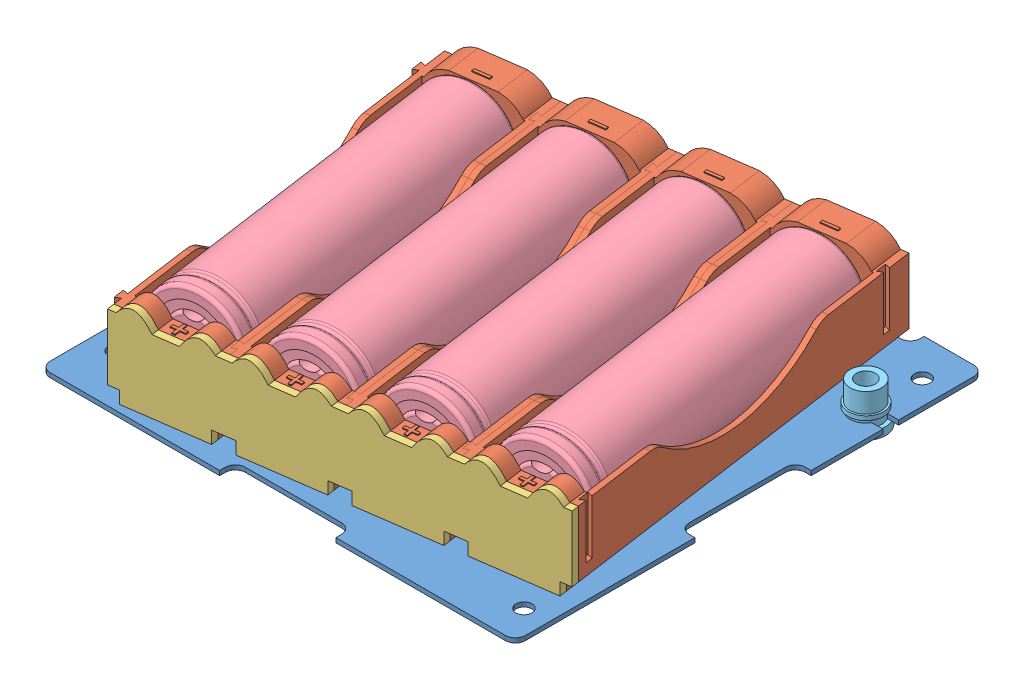
SolidWorks assembly M100 Battery Assembly, configuration Default. Lengths in mm.
Overall size (95.95 22.45 94.09).
45 component instances, 8 part files, 97 mates.
Components (placement in the parent):
- M103 Battery Plate-1: M103 Battery Plate [Default] at (-64.3857 -9.2767 40.2779) size (95.46 0.9 94.09)
- M102 Battery Holder Assembly-1: M102 Battery Holder Assembly [Default] at (-18.4887 8.3398 -10.8914) x (-0.990268 0 0.139173) z (-0.139173 0 -0.990268) size (83.6 18.9 79.5)
  - single battery holder-1: single battery holder [Default] at (-25.8788 -16.7165 25.0128) size (21.65 18.9 78)
  - single battery holder-2: single battery holder [Default] at (-5.2288 -16.7165 25.0128) size (21.65 18.9 78)
  - single battery holder-3: single battery holder [Default] at (15.4212 -16.7165 25.0128) size (21.65 18.9 78)
  - single battery holder-4: single battery holder [Default] at (36.0712 -16.7165 25.0128) size (21.65 18.9 78)
  - battery pack cap-1: battery pack cap [Default] at (36.0712 -16.7165 -52.9872) x (-1 0 0) z (0 0 -1) size (82.6 17.7 1.5)
- Battery, 18650_LGABC11865_3.7V-1: Battery, 18650_LGABC11865_3.7V [Default] at (9.3368 2.4733 1.1504) x (-0.990268 0 0.139173) z (0 1 0) size (18.3 64.95 18.3)
- Battery, 18650_LGABC11865_3.7V-2: Battery, 18650_LGABC11865_3.7V [Default] at (-11.1122 2.4733 4.0244) x (-0.990268 0 0.139173) z (0 1 0) size (18.3 64.95 18.3)
- Battery, 18650_LGABC11865_3.7V-3: Battery, 18650_LGABC11865_3.7V [Default] at (-31.5612 2.4733 6.8983) x (-0.990268 0 0.139173) z (0 1 0) size (18.3 64.95 18.3)
- Battery, 18650_LGABC11865_3.7V-4: Battery, 18650_LGABC11865_3.7V [Default] at (-52.0103 2.4733 9.7722) x (-0.990268 0 0.139173) z (0 1 0) size (18.3 64.95 18.3)
- grommet, 1-8in ID, 5269T211-2: grommet, 1-8in ID, 5269T211 [Default] at (21.2068 -2.8902 -24.7221) x (0.837169 0 0.546944) z (0.546944 0 -0.837169) size (7.94 7.94 7.94)
- screw, pan head, 0-80, 1_8L, 316SS, 91400A030-9: screw, pan head, 0-80, 1_8L, 316SS, 91400A030 [91400A030] at (-49.1372 -6.1017 -8.9448) x (-0.837169 0 -0.546944) z (0 -1 0) size (2.95 2.95 4.29)
- screw, pan head, 0-80, 1_8L, 316SS, 91400A030-10: screw, pan head, 0-80, 1_8L, 316SS, 91400A030 [91400A030] at (-39.4821 -6.1017 -10.3017) x (-0.837169 0 -0.546944) z (0 -1 0) size (2.95 2.95 4.29)
- screw, pan head, 0-80, 1_8L, 316SS, 91400A030-11: screw, pan head, 0-80, 1_8L, 316SS, 91400A030 [91400A030] at (-59.9311 -6.1017 -7.4278) x (-0.837169 0 -0.546944) z (0 -1 0) size (2.95 2.95 4.29)
- screw, pan head, 0-80, 1_8L, 316SS, 91400A030-12: screw, pan head, 0-80, 1_8L, 316SS, 91400A030 [91400A030] at (-28.6882 -6.1017 -11.8187) x (-0.837169 0 -0.546944) z (0 -1 0) size (2.95 2.95 4.29)
- screw, pan head, 0-80, 1_8L, 316SS, 91400A030-13: screw, pan head, 0-80, 1_8L, 316SS, 91400A030 [91400A030] at (-55.1157 -6.1017 26.8355) x (-0.837169 0 -0.546944) z (0 -1 0) size (2.95 2.95 4.29)
- screw, pan head, 0-80, 1_8L, 316SS, 91400A030-14: screw, pan head, 0-80, 1_8L, 316SS, 91400A030 [91400A030] at (-44.3218 -6.1017 25.3185) x (-0.837169 0 -0.546944) z (0 -1 0) size (2.95 2.95 4.29)
- screw, pan head, 0-80, 1_8L, 316SS, 91400A030-15: screw, pan head, 0-80, 1_8L, 316SS, 91400A030 [91400A030] at (17.0253 -6.1017 16.6967) x (1 0 0) z (0 -1 0) size (2.95 2.95 4.29)
- screw, pan head, 0-80, 1_8L, 316SS, 91400A030-16: screw, pan head, 0-80, 1_8L, 316SS, 91400A030 [91400A030] at (-34.6667 -6.1017 23.9615) x (-0.837169 0 -0.546944) z (0 -1 0) size (2.95 2.95 4.29)
- screw, pan head, 0-80, 1_8L, 316SS, 91400A030-17: screw, pan head, 0-80, 1_8L, 316SS, 91400A030 [91400A030] at (12.2099 -6.1017 -17.5666) x (-0.837169 0 -0.546944) z (0 -1 0) size (2.95 2.95 4.29)
- screw, pan head, 0-80, 1_8L, 316SS, 91400A030-18: screw, pan head, 0-80, 1_8L, 316SS, 91400A030 [91400A030] at (-19.0331 -6.1017 -13.1757) x (-0.837169 0 -0.546944) z (0 -1 0) size (2.95 2.95 4.29)
- screw, pan head, 0-80, 1_8L, 316SS, 91400A030-19: screw, pan head, 0-80, 1_8L, 316SS, 91400A030 [91400A030] at (-8.2391 -6.1017 -14.6926) x (-0.837169 0 -0.546944) z (0 -1 0) size (2.95 2.95 4.29)
- screw, pan head, 0-80, 1_8L, 316SS, 91400A030-20: screw, pan head, 0-80, 1_8L, 316SS, 91400A030 [91400A030] at (1.416 -6.1017 -16.0496) x (-0.837169 0 -0.546944) z (0 -1 0) size (2.95 2.95 4.29)
- screw, pan head, 0-80, 1_8L, 316SS, 91400A030-21: screw, pan head, 0-80, 1_8L, 316SS, 91400A030 [91400A030] at (-23.8728 -6.1017 22.4446) x (-0.837169 0 -0.546944) z (0 -1 0) size (2.95 2.95 4.29)
- screw, pan head, 0-80, 1_8L, 316SS, 91400A030-22: screw, pan head, 0-80, 1_8L, 316SS, 91400A030 [91400A030] at (-14.2177 -6.1017 21.0876) x (-0.837169 0 -0.546944) z (0 -1 0) size (2.95 2.95 4.29)
- screw, pan head, 0-80, 1_8L, 316SS, 91400A030-23: screw, pan head, 0-80, 1_8L, 316SS, 91400A030 [91400A030] at (-3.4238 -6.1017 19.5706) x (-0.837169 0 -0.546944) z (0 -1 0) size (2.95 2.95 4.29)
- screw, pan head, 0-80, 1_8L, 316SS, 91400A030-24: screw, pan head, 0-80, 1_8L, 316SS, 91400A030 [91400A030] at (6.2314 -6.1017 18.2137) x (-0.837169 0 -0.546944) z (0 -1 0) size (2.95 2.95 4.29)
- nut, 0-80, standard, 18-8SS, 91841A115-1: nut, 0-80, standard, 18-8SS, 91841A115 [91841A115] at (1.4049 -7.9267 -16.0638) x (0.788011 0 -0.615661) z (0.615661 0 0.788011) size (3.97 1.19 5.04)
- nut, 0-80, standard, 18-8SS, 91841A115-2: nut, 0-80, standard, 18-8SS, 91841A115 [91841A115] at (-14.2177 -7.9267 21.0876) x (-0.990268 0 0.139173) z (-0.139173 0 -0.990268) size (3.97 1.19 5.04)
- nut, 0-80, standard, 18-8SS, 91841A115-3: nut, 0-80, standard, 18-8SS, 91841A115 [91841A115] at (-3.4238 -7.9267 19.5706) x (-0.990268 0 0.139173) z (-0.139173 0 -0.990268) size (3.97 1.19 5.04)
- nut, 0-80, standard, 18-8SS, 91841A115-4: nut, 0-80, standard, 18-8SS, 91841A115 [91841A115] at (-8.2391 -7.9267 -14.6926) x (-0.990268 0 0.139173) z (-0.139173 0 -0.990268) size (3.97 1.19 5.04)
- nut, 0-80, standard, 18-8SS, 91841A115-5: nut, 0-80, standard, 18-8SS, 91841A115 [91841A115] at (-19.0331 -7.9267 -13.1757) x (-0.990268 0 0.139173) z (-0.139173 0 -0.990268) size (3.97 1.19 5.04)
- nut, 0-80, standard, 18-8SS, 91841A115-6: nut, 0-80, standard, 18-8SS, 91841A115 [91841A115] at (-39.4821 -7.9267 -10.3017) x (-0.990268 0 0.139173) z (-0.139173 0 -0.990268) size (3.97 1.19 5.04)
- nut, 0-80, standard, 18-8SS, 91841A115-7: nut, 0-80, standard, 18-8SS, 91841A115 [91841A115] at (-28.6882 -7.9267 -11.8187) x (-0.990268 0 0.139173) z (-0.139173 0 -0.990268) size (3.97 1.19 5.04)
- nut, 0-80, standard, 18-8SS, 91841A115-8: nut, 0-80, standard, 18-8SS, 91841A115 [91841A115] at (-23.8728 -7.9267 22.4446) x (-0.990268 0 0.139173) z (-0.139173 0 -0.990268) size (3.97 1.19 5.04)
- nut, 0-80, standard, 18-8SS, 91841A115-9: nut, 0-80, standard, 18-8SS, 91841A115 [91841A115] at (-34.6667 -7.9267 23.9615) x (-0.990268 0 0.139173) z (-0.139173 0 -0.990268) size (3.97 1.19 5.04)
- nut, 0-80, standard, 18-8SS, 91841A115-10: nut, 0-80, standard, 18-8SS, 91841A115 [91841A115] at (-59.9311 -7.9267 -7.4278) x (-0.990268 0 0.139173) z (-0.139173 0 -0.990268) size (3.97 1.19 5.04)
- nut, 0-80, standard, 18-8SS, 91841A115-11: nut, 0-80, standard, 18-8SS, 91841A115 [91841A115] at (-49.1372 -7.9267 -8.9448) x (-0.990268 0 0.139173) z (-0.139173 0 -0.990268) size (3.97 1.19 5.04)
- nut, 0-80, standard, 18-8SS, 91841A115-12: nut, 0-80, standard, 18-8SS, 91841A115 [91841A115] at (-44.3218 -7.9267 25.3185) x (-0.990268 0 0.139173) z (-0.139173 0 -0.990268) size (3.97 1.19 5.04)
- nut, 0-80, standard, 18-8SS, 91841A115-13: nut, 0-80, standard, 18-8SS, 91841A115 [91841A115] at (-55.1157 -7.9267 26.8355) x (-0.990268 0 0.139173) z (-0.139173 0 -0.990268) size (3.97 1.19 5.04)
- nut, 0-80, standard, 18-8SS, 91841A115-14: nut, 0-80, standard, 18-8SS, 91841A115 [91841A115] at (6.2314 -7.9267 18.2137) x (-0.990268 0 0.139173) z (-0.139173 0 -0.990268) size (3.97 1.19 5.04)
- nut, 0-80, standard, 18-8SS, 91841A115-15: nut, 0-80, standard, 18-8SS, 91841A115 [91841A115] at (17.0253 -7.9267 16.6967) x (-0.990268 0 0.139173) z (-0.139173 0 -0.990268) size (3.97 1.19 5.04)
- nut, 0-80, standard, 18-8SS, 91841A115-16: nut, 0-80, standard, 18-8SS, 91841A115 [91841A115] at (12.2099 -7.9267 -17.5666) x (-0.990268 0 0.139173) z (-0.139173 0 -0.990268) size (3.97 1.19 5.04)
- SCOTCH WELD EC2216-1: SCOTCH WELD EC2216 [Default] at origin
Mates (geometry in assembly coordinates):
- Coincident1: coincident anti-aligned: plane of M103 Battery Plate-1 through (-69.2532 -8.3767 -36.7907) normal (0 1 0); plane of M102 Battery Holder Assembly-1/single battery holder-4 through (-60.2184 -8.3767 10.1078) normal (0 -1 0)
- Angle1: planar angle = 0.139626 rad anti-aligned: plane of assembly through (0 0 0) normal (1 0 0); plane of M102 Battery Holder Assembly-1 through (-18.4887 8.3398 -10.8914) normal (-0.990268 0 0.139173)
- Concentric4: concentric aligned: cylinder of M103 Battery Plate-1 through (21.2068 -9.2767 -24.7221) axis (0 1 0) radius 3.175; cylinder of grommet, 1-8in ID, 5269T211-2 through (21.2068 -2.8902 -24.7221) axis (0 1 0) radius 3.175
- Coincident3: coincident anti-aligned: plane of grommet, 1-8in ID, 5269T211-2 through (24.5293 -9.2767 -22.5514) normal (0 1 0); plane of M103 Battery Plate-1 through (-69.2532 -9.2767 -36.7907) normal (0 -1 0)
- Coincident4: coincident anti-aligned: plane of M103 Battery Plate-1 through (-69.2532 -9.2767 -36.7907) normal (0 -1 0); plane of screw, pan head, 0-80, 1_8L, 316SS, 91400A030-13 through (-55.1157 -9.2767 26.8355) normal (0 1 0)
- Coincident5: coincident anti-aligned: plane of M103 Battery Plate-1 through (-69.2532 -9.2767 -36.7907) normal (0 -1 0); plane of screw, pan head, 0-80, 1_8L, 316SS, 91400A030-16 through (-34.6667 -9.2767 23.9615) normal (0 1 0)
- Coincident6: coincident anti-aligned: plane of M103 Battery Plate-1 through (-69.2532 -9.2767 -36.7907) normal (0 -1 0); plane of screw, pan head, 0-80, 1_8L, 316SS, 91400A030-14 through (-44.3218 -9.2767 25.3185) normal (0 1 0)
- Coincident7: coincident anti-aligned: plane of M103 Battery Plate-1 through (-69.2532 -9.2767 -36.7907) normal (0 -1 0); plane of screw, pan head, 0-80, 1_8L, 316SS, 91400A030-23 through (-3.4238 -9.2767 19.5706) normal (0 1 0)
- Coincident8: coincident anti-aligned: plane of M103 Battery Plate-1 through (-69.2532 -9.2767 -36.7907) normal (0 -1 0); plane of screw, pan head, 0-80, 1_8L, 316SS, 91400A030-24 through (6.2314 -9.2767 18.2137) normal (0 1 0)
- Coincident9: coincident anti-aligned: plane of M103 Battery Plate-1 through (-69.2532 -9.2767 -36.7907) normal (0 -1 0); plane of screw, pan head, 0-80, 1_8L, 316SS, 91400A030-22 through (-14.2177 -9.2767 21.0876) normal (0 1 0)
- Coincident10: coincident anti-aligned: plane of M103 Battery Plate-1 through (-69.2532 -9.2767 -36.7907) normal (0 -1 0); plane of screw, pan head, 0-80, 1_8L, 316SS, 91400A030-11 through (-59.9311 -9.2767 -7.4278) normal (0 1 0)
- Coincident11: coincident anti-aligned: plane of M103 Battery Plate-1 through (-69.2532 -9.2767 -36.7907) normal (0 -1 0); plane of screw, pan head, 0-80, 1_8L, 316SS, 91400A030-21 through (-23.8728 -9.2767 22.4446) normal (0 1 0)
- Coincident12: coincident anti-aligned: plane of M103 Battery Plate-1 through (-69.2532 -9.2767 -36.7907) normal (0 -1 0); plane of screw, pan head, 0-80, 1_8L, 316SS, 91400A030-12 through (-28.6882 -9.2767 -11.8187) normal (0 1 0)
- Coincident13: coincident anti-aligned: plane of M103 Battery Plate-1 through (-69.2532 -9.2767 -36.7907) normal (0 -1 0); plane of screw, pan head, 0-80, 1_8L, 316SS, 91400A030-9 through (-49.1372 -9.2767 -8.9448) normal (0 1 0)
- Coincident14: coincident anti-aligned: plane of M103 Battery Plate-1 through (-69.2532 -9.2767 -36.7907) normal (0 -1 0); plane of screw, pan head, 0-80, 1_8L, 316SS, 91400A030-10 through (-39.4821 -9.2767 -10.3017) normal (0 1 0)
- Coincident15: coincident anti-aligned: plane of M103 Battery Plate-1 through (-69.2532 -9.2767 -36.7907) normal (0 -1 0); plane of screw, pan head, 0-80, 1_8L, 316SS, 91400A030-18 through (-19.0331 -9.2767 -13.1757) normal (0 1 0)
- Coincident16: coincident anti-aligned: plane of M103 Battery Plate-1 through (-69.2532 -9.2767 -36.7907) normal (0 -1 0); plane of screw, pan head, 0-80, 1_8L, 316SS, 91400A030-19 through (-8.2391 -9.2767 -14.6926) normal (0 1 0)
- Coincident17: coincident anti-aligned: plane of M103 Battery Plate-1 through (-69.2532 -9.2767 -36.7907) normal (0 -1 0); plane of screw, pan head, 0-80, 1_8L, 316SS, 91400A030-20 through (1.416 -9.2767 -16.0496) normal (0 1 0)
- Coincident18: coincident anti-aligned: plane of M103 Battery Plate-1 through (-69.2532 -9.2767 -36.7907) normal (0 -1 0); plane of screw, pan head, 0-80, 1_8L, 316SS, 91400A030-17 through (12.2099 -9.2767 -17.5666) normal (0 1 0)
- Coincident20: coincident anti-aligned: plane of M103 Battery Plate-1 through (-69.2532 -9.2767 -36.7907) normal (0 -1 0); plane of screw, pan head, 0-80, 1_8L, 316SS, 91400A030-15 through (17.0253 -9.2767 16.6967) normal (0 1 0)
- Concentric5: concentric anti-aligned: circle of M103 Battery Plate-1; circle of screw, pan head, 0-80, 1_8L, 316SS, 91400A030-17
- Concentric6: concentric anti-aligned: circle of screw, pan head, 0-80, 1_8L, 316SS, 91400A030-20; circle of M103 Battery Plate-1
- Concentric7: concentric anti-aligned: circle of M103 Battery Plate-1; circle of screw, pan head, 0-80, 1_8L, 316SS, 91400A030-19
- Concentric8: concentric anti-aligned: circle of M103 Battery Plate-1; circle of screw, pan head, 0-80, 1_8L, 316SS, 91400A030-18
- Concentric9: concentric anti-aligned: circle of M103 Battery Plate-1; circle of screw, pan head, 0-80, 1_8L, 316SS, 91400A030-12
- Concentric10: concentric anti-aligned: circle of M103 Battery Plate-1; circle of screw, pan head, 0-80, 1_8L, 316SS, 91400A030-10
- Concentric11: concentric anti-aligned: circle of M103 Battery Plate-1; circle of screw, pan head, 0-80, 1_8L, 316SS, 91400A030-9
- Concentric12: concentric anti-aligned: circle of M103 Battery Plate-1; circle of screw, pan head, 0-80, 1_8L, 316SS, 91400A030-11
- Concentric13: concentric anti-aligned: circle of M103 Battery Plate-1; circle of screw, pan head, 0-80, 1_8L, 316SS, 91400A030-24
- Concentric14: concentric anti-aligned: circle of M103 Battery Plate-1; circle of screw, pan head, 0-80, 1_8L, 316SS, 91400A030-23
- Concentric15: concentric anti-aligned: circle of M103 Battery Plate-1; circle of screw, pan head, 0-80, 1_8L, 316SS, 91400A030-22
- Concentric16: concentric anti-aligned: circle of M103 Battery Plate-1; circle of screw, pan head, 0-80, 1_8L, 316SS, 91400A030-21
- Concentric17: concentric anti-aligned: circle of M103 Battery Plate-1; circle of screw, pan head, 0-80, 1_8L, 316SS, 91400A030-16
- Concentric18: concentric anti-aligned: circle of M103 Battery Plate-1; circle of screw, pan head, 0-80, 1_8L, 316SS, 91400A030-14
- Concentric19: concentric anti-aligned: circle of M103 Battery Plate-1; circle of screw, pan head, 0-80, 1_8L, 316SS, 91400A030-13
- Concentric20: concentric anti-aligned: circle of M103 Battery Plate-1; circle of screw, pan head, 0-80, 1_8L, 316SS, 91400A030-15
- Coincident21: coincident aligned: plane of M102 Battery Holder Assembly-1/single battery holder-1 through (3.6572 -8.3767 -39.2624) normal (-0.990268 0 0.139173); plane of Battery, 18650_LGABC11865_3.7V-1 through (9.3368 2.4733 1.1504) normal (-0.990268 0 0.139173)
- Tangent1: tangent anti-aligned: plane of M102 Battery Holder Assembly-1/single battery holder-1 through (3.6572 11.6233 -39.2624) normal (0 -1 0); cylinder of Battery, 18650_LGABC11865_3.7V-1 through (13.853 2.4733 33.2846) axis (-0.139173 0 -0.990268) radius 9.15
- Distance1: distance = 1.5 mm anti-aligned: plane of Battery, 18650_LGABC11865_3.7V-1 through (4.8207 2.4733 -30.9838) normal (-0.139173 0 -0.990268); plane of M102 Battery Holder Assembly-1/single battery holder-1 through (8.0778 4.225 -32.9563) normal (0.139173 0 0.990268)
- Coincident19: coincident aligned: plane of Battery, 18650_LGABC11865_3.7V-2 through (-15.6284 2.4733 -28.1098) normal (-0.139173 0 -0.990268); plane of Battery, 18650_LGABC11865_3.7V-1 through (4.8207 2.4733 -30.9838) normal (-0.139173 0 -0.990268)
- Coincident22: coincident aligned: plane of M102 Battery Holder Assembly-1/single battery holder-2 through (-16.7919 -8.3767 -36.3885) normal (-0.990268 0 0.139173); plane of Battery, 18650_LGABC11865_3.7V-2 through (-11.1122 2.4733 4.0244) normal (-0.990268 0 0.139173)
- Tangent2: tangent anti-aligned: plane of M102 Battery Holder Assembly-1/single battery holder-2 through (-16.7919 11.6233 -36.3885) normal (0 -1 0); cylinder of Battery, 18650_LGABC11865_3.7V-2 through (-6.596 2.4733 36.1586) axis (-0.139173 0 -0.990268) radius 9.15
- Coincident23: coincident aligned: plane of Battery, 18650_LGABC11865_3.7V-2 through (-15.6284 2.4733 -28.1098) normal (-0.139173 0 -0.990268); plane of Battery, 18650_LGABC11865_3.7V-3 through (-36.0774 2.4733 -25.2359) normal (-0.139173 0 -0.990268)
- Coincident24: coincident aligned: plane of M102 Battery Holder Assembly-1/single battery holder-3 through (-37.2409 -8.3767 -33.5146) normal (-0.990268 0 0.139173); plane of Battery, 18650_LGABC11865_3.7V-3 through (-31.5612 2.4733 6.8983) normal (-0.990268 0 0.139173)
- Tangent3: tangent anti-aligned: plane of M102 Battery Holder Assembly-1/single battery holder-3 through (-37.2409 11.6233 -33.5146) normal (0 -1 0); cylinder of Battery, 18650_LGABC11865_3.7V-3 through (-27.0451 2.4733 39.0325) axis (-0.139173 0 -0.990268) radius 9.15
- Coincident25: coincident aligned: plane of Battery, 18650_LGABC11865_3.7V-4 through (-56.5264 2.4733 -22.362) normal (-0.139173 0 -0.990268); plane of Battery, 18650_LGABC11865_3.7V-3 through (-36.0774 2.4733 -25.2359) normal (-0.139173 0 -0.990268)
- Coincident26: coincident aligned: plane of M102 Battery Holder Assembly-1/single battery holder-4 through (-57.6899 -8.3767 -30.6406) normal (-0.990268 0 0.139173); plane of Battery, 18650_LGABC11865_3.7V-4 through (-52.0103 2.4733 9.7722) normal (-0.990268 0 0.139173)
- Tangent4: tangent anti-aligned: cylinder of Battery, 18650_LGABC11865_3.7V-4 through (-47.4941 2.4733 41.9064) axis (-0.139173 0 -0.990268) radius 9.15; plane of M102 Battery Holder Assembly-1/single battery holder-4 through (-57.6899 11.6233 -30.6406) normal (0 -1 0)
- Concentric21: concentric aligned: cylinder of M103 Battery Plate-1 through (12.2099 -8.3767 -17.5666) axis (0 -1 0) radius 0.925; cylinder of M102 Battery Holder Assembly-1/single battery holder-1 through (12.2099 10.3234 -17.5666) axis (0 -1 0) radius 0.925
- Coincident27: coincident anti-aligned: plane of nut, 0-80, standard, 18-8SS, 91841A115-1 through (-0.0058 -7.9267 -17.8694) normal (0 -1 0); plane of M102 Battery Holder Assembly-1/single battery holder-1 through (3.7029 -7.9267 -16.371) normal (0 1 0)
- Coincident28: coincident anti-aligned: plane of nut, 0-80, standard, 18-8SS, 91841A115-1 through (2.2632 -6.736 -18.1883) normal (-0.139173 0 -0.990268); plane of M102 Battery Holder Assembly-1/single battery holder-1 through (2.2811 10.3234 -18.1908) normal (0.139173 0 0.990268)
- Coincident29: coincident anti-aligned: plane of nut, 0-80, standard, 18-8SS, 91841A115-1 through (-0.0058 -6.736 -17.8694) normal (-0.927184 0 -0.374607); plane of M102 Battery Holder Assembly-1/single battery holder-1 through (-0.0058 10.3234 -17.8694) normal (0.927184 0 0.374607)
- Coincident33: coincident aligned: plane of nut, 0-80, standard, 18-8SS, 91841A115-16 through (12.5288 -7.9267 -15.2975) normal (0 -1 0); plane of nut, 0-80, standard, 18-8SS, 91841A115-2 through (-13.8988 -7.9267 23.3567) normal (0 -1 0)
- Parallel15: parallel aligned: plane of M102 Battery Holder Assembly-1 through (-18.4887 8.3398 -10.8914) normal (-0.139173 0 -0.990268); plane of nut, 0-80, standard, 18-8SS, 91841A115-2 through (-14.2177 -7.9267 21.0876) normal (-0.139173 0 -0.990268)
- Concentric22: concentric aligned: circle of M102 Battery Holder Assembly-1/single battery holder-2; circle of nut, 0-80, standard, 18-8SS, 91841A115-2
- Coincident31: coincident aligned: plane of nut, 0-80, standard, 18-8SS, 91841A115-16 through (12.5288 -7.9267 -15.2975) normal (0 -1 0); plane of nut, 0-80, standard, 18-8SS, 91841A115-3 through (-3.1049 -7.9267 21.8397) normal (0 -1 0)
- Parallel1: parallel aligned: plane of M102 Battery Holder Assembly-1 through (-18.4887 8.3398 -10.8914) normal (-0.139173 0 -0.990268); plane of nut, 0-80, standard, 18-8SS, 91841A115-3 through (-3.4238 -7.9267 19.5706) normal (-0.139173 0 -0.990268)
- Concentric23: concentric aligned: circle of M102 Battery Holder Assembly-1/single battery holder-2; circle of nut, 0-80, standard, 18-8SS, 91841A115-3
- Coincident32: coincident aligned: plane of nut, 0-80, standard, 18-8SS, 91841A115-16 through (12.5288 -7.9267 -15.2975) normal (0 -1 0); plane of nut, 0-80, standard, 18-8SS, 91841A115-4 through (-7.9202 -7.9267 -12.4236) normal (0 -1 0)
- Parallel2: parallel aligned: plane of M102 Battery Holder Assembly-1 through (-18.4887 8.3398 -10.8914) normal (-0.139173 0 -0.990268); plane of nut, 0-80, standard, 18-8SS, 91841A115-4 through (-8.2391 -7.9267 -14.6926) normal (-0.139173 0 -0.990268)
- Concentric24: concentric aligned: circle of M102 Battery Holder Assembly-1/single battery holder-2; circle of nut, 0-80, standard, 18-8SS, 91841A115-4
- Coincident34: coincident aligned: plane of nut, 0-80, standard, 18-8SS, 91841A115-16 through (12.5288 -7.9267 -15.2975) normal (0 -1 0); plane of nut, 0-80, standard, 18-8SS, 91841A115-5 through (-18.7142 -7.9267 -10.9066) normal (0 -1 0)
- Parallel3: parallel aligned: plane of M102 Battery Holder Assembly-1 through (-18.4887 8.3398 -10.8914) normal (-0.139173 0 -0.990268); plane of nut, 0-80, standard, 18-8SS, 91841A115-5 through (-19.0331 -7.9267 -13.1757) normal (-0.139173 0 -0.990268)
- Concentric25: concentric aligned: circle of M102 Battery Holder Assembly-1/single battery holder-2; circle of nut, 0-80, standard, 18-8SS, 91841A115-5
- Coincident37: coincident aligned: plane of nut, 0-80, standard, 18-8SS, 91841A115-16 through (12.5288 -7.9267 -15.2975) normal (0 -1 0); plane of nut, 0-80, standard, 18-8SS, 91841A115-6 through (-39.1632 -7.9267 -8.0327) normal (0 -1 0)
- Parallel4: parallel aligned: plane of M102 Battery Holder Assembly-1 through (-18.4887 8.3398 -10.8914) normal (-0.139173 0 -0.990268); plane of nut, 0-80, standard, 18-8SS, 91841A115-6 through (-39.4821 -7.9267 -10.3017) normal (-0.139173 0 -0.990268)
- Concentric26: concentric aligned: circle of M102 Battery Holder Assembly-1/single battery holder-3; circle of nut, 0-80, standard, 18-8SS, 91841A115-6
- Coincident36: coincident aligned: plane of nut, 0-80, standard, 18-8SS, 91841A115-16 through (12.5288 -7.9267 -15.2975) normal (0 -1 0); plane of nut, 0-80, standard, 18-8SS, 91841A115-7 through (-28.3693 -7.9267 -9.5497) normal (0 -1 0)
- Parallel5: parallel aligned: plane of M102 Battery Holder Assembly-1 through (-18.4887 8.3398 -10.8914) normal (-0.139173 0 -0.990268); plane of nut, 0-80, standard, 18-8SS, 91841A115-7 through (-28.6882 -7.9267 -11.8187) normal (-0.139173 0 -0.990268)
- Concentric27: concentric aligned: circle of M102 Battery Holder Assembly-1/single battery holder-3; circle of nut, 0-80, standard, 18-8SS, 91841A115-7
- Coincident35: coincident aligned: plane of nut, 0-80, standard, 18-8SS, 91841A115-16 through (12.5288 -7.9267 -15.2975) normal (0 -1 0); plane of nut, 0-80, standard, 18-8SS, 91841A115-8 through (-23.5539 -7.9267 24.7136) normal (0 -1 0)
- Parallel6: parallel aligned: plane of M102 Battery Holder Assembly-1 through (-18.4887 8.3398 -10.8914) normal (-0.139173 0 -0.990268); plane of nut, 0-80, standard, 18-8SS, 91841A115-8 through (-23.8728 -7.9267 22.4446) normal (-0.139173 0 -0.990268)
- Concentric28: concentric aligned: circle of M102 Battery Holder Assembly-1/single battery holder-3; circle of nut, 0-80, standard, 18-8SS, 91841A115-8
- Coincident38: coincident aligned: plane of nut, 0-80, standard, 18-8SS, 91841A115-16 through (12.5288 -7.9267 -15.2975) normal (0 -1 0); plane of nut, 0-80, standard, 18-8SS, 91841A115-9 through (-34.3478 -7.9267 26.2306) normal (0 -1 0)
- Parallel7: parallel aligned: plane of M102 Battery Holder Assembly-1 through (-18.4887 8.3398 -10.8914) normal (-0.139173 0 -0.990268); plane of nut, 0-80, standard, 18-8SS, 91841A115-9 through (-34.6667 -7.9267 23.9615) normal (-0.139173 0 -0.990268)
- Concentric29: concentric aligned: circle of M102 Battery Holder Assembly-1/single battery holder-3; circle of nut, 0-80, standard, 18-8SS, 91841A115-9
- Coincident42: coincident aligned: plane of nut, 0-80, standard, 18-8SS, 91841A115-16 through (12.5288 -7.9267 -15.2975) normal (0 -1 0); plane of nut, 0-80, standard, 18-8SS, 91841A115-10 through (-59.6122 -7.9267 -5.1588) normal (0 -1 0)
- Parallel8: parallel aligned: plane of M102 Battery Holder Assembly-1 through (-18.4887 8.3398 -10.8914) normal (-0.139173 0 -0.990268); plane of nut, 0-80, standard, 18-8SS, 91841A115-10 through (-59.9311 -7.9267 -7.4278) normal (-0.139173 0 -0.990268)
- Concentric30: concentric aligned: circle of M102 Battery Holder Assembly-1/single battery holder-4; circle of nut, 0-80, standard, 18-8SS, 91841A115-10
- Coincident39: coincident aligned: plane of nut, 0-80, standard, 18-8SS, 91841A115-16 through (12.5288 -7.9267 -15.2975) normal (0 -1 0); plane of nut, 0-80, standard, 18-8SS, 91841A115-11 through (-48.8183 -7.9267 -6.6757) normal (0 -1 0)
- Parallel14: parallel aligned: plane of M102 Battery Holder Assembly-1 through (-18.4887 8.3398 -10.8914) normal (-0.139173 0 -0.990268); plane of nut, 0-80, standard, 18-8SS, 91841A115-11 through (-49.1372 -7.9267 -8.9448) normal (-0.139173 0 -0.990268)
- Concentric31: concentric aligned: circle of M102 Battery Holder Assembly-1/single battery holder-4; circle of nut, 0-80, standard, 18-8SS, 91841A115-11
- Coincident40: coincident aligned: plane of nut, 0-80, standard, 18-8SS, 91841A115-16 through (12.5288 -7.9267 -15.2975) normal (0 -1 0); plane of nut, 0-80, standard, 18-8SS, 91841A115-12 through (-44.0029 -7.9267 27.5875) normal (0 -1 0)
- Parallel9: parallel aligned: plane of M102 Battery Holder Assembly-1 through (-18.4887 8.3398 -10.8914) normal (-0.139173 0 -0.990268); plane of nut, 0-80, standard, 18-8SS, 91841A115-12 through (-44.3218 -7.9267 25.3185) normal (-0.139173 0 -0.990268)
- Concentric32: concentric aligned: circle of M102 Battery Holder Assembly-1/single battery holder-4; circle of nut, 0-80, standard, 18-8SS, 91841A115-12
- Coincident41: coincident aligned: plane of nut, 0-80, standard, 18-8SS, 91841A115-16 through (12.5288 -7.9267 -15.2975) normal (0 -1 0); plane of nut, 0-80, standard, 18-8SS, 91841A115-13 through (-54.7969 -7.9267 29.1045) normal (0 -1 0)
- Parallel10: parallel aligned: plane of M102 Battery Holder Assembly-1 through (-18.4887 8.3398 -10.8914) normal (-0.139173 0 -0.990268); plane of nut, 0-80, standard, 18-8SS, 91841A115-13 through (-55.1157 -7.9267 26.8355) normal (-0.139173 0 -0.990268)
- Concentric33: concentric aligned: circle of M102 Battery Holder Assembly-1/single battery holder-4; circle of nut, 0-80, standard, 18-8SS, 91841A115-13
- Coincident30: coincident aligned: plane of nut, 0-80, standard, 18-8SS, 91841A115-16 through (12.5288 -7.9267 -15.2975) normal (0 -1 0); plane of nut, 0-80, standard, 18-8SS, 91841A115-14 through (6.5503 -7.9267 20.4828) normal (0 -1 0)
- Parallel11: parallel aligned: plane of M102 Battery Holder Assembly-1 through (-18.4887 8.3398 -10.8914) normal (-0.139173 0 -0.990268); plane of nut, 0-80, standard, 18-8SS, 91841A115-14 through (6.2314 -7.9267 18.2137) normal (-0.139173 0 -0.990268)
- Concentric34: concentric aligned: circle of M102 Battery Holder Assembly-1/single battery holder-1; circle of nut, 0-80, standard, 18-8SS, 91841A115-14
- Coincident43: coincident aligned: plane of nut, 0-80, standard, 18-8SS, 91841A115-16 through (12.5288 -7.9267 -15.2975) normal (0 -1 0); plane of nut, 0-80, standard, 18-8SS, 91841A115-15 through (17.3442 -7.9267 18.9658) normal (0 -1 0)
- Parallel12: parallel aligned: plane of M102 Battery Holder Assembly-1 through (-18.4887 8.3398 -10.8914) normal (-0.139173 0 -0.990268); plane of nut, 0-80, standard, 18-8SS, 91841A115-15 through (17.0253 -7.9267 16.6967) normal (-0.139173 0 -0.990268)
- Concentric35: concentric aligned: circle of M102 Battery Holder Assembly-1/single battery holder-1; circle of nut, 0-80, standard, 18-8SS, 91841A115-15
- Coincident44: coincident anti-aligned: plane of nut, 0-80, standard, 18-8SS, 91841A115-16 through (12.5288 -7.9267 -15.2975) normal (0 -1 0); plane of M102 Battery Holder Assembly-1/single battery holder-1 through (9.923 -7.9267 -17.2452) normal (0 1 0)
- Parallel13: parallel aligned: plane of M102 Battery Holder Assembly-1 through (-18.4887 8.3398 -10.8914) normal (-0.139173 0 -0.990268); plane of nut, 0-80, standard, 18-8SS, 91841A115-16 through (12.2099 -7.9267 -17.5666) normal (-0.139173 0 -0.990268)
- Concentric36: concentric aligned: circle of M102 Battery Holder Assembly-1/single battery holder-1; circle of nut, 0-80, standard, 18-8SS, 91841A115-16
